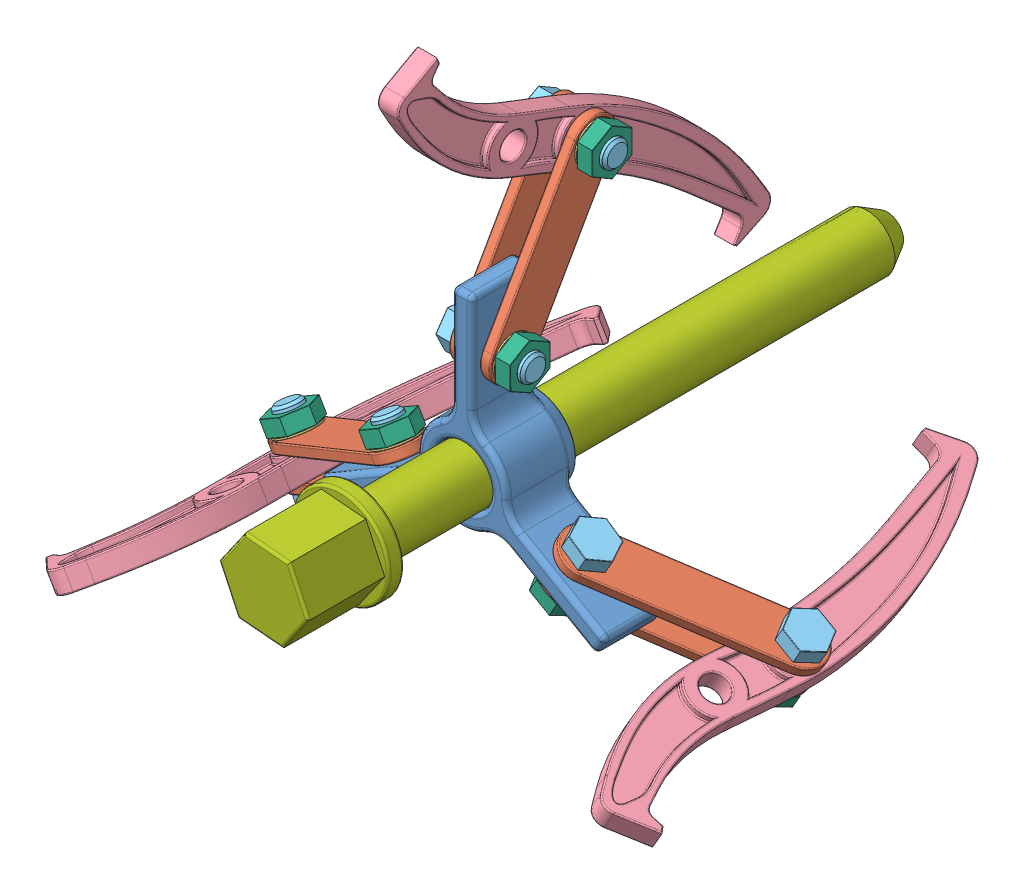
SolidWorks assembly Assem1, configuration Predeterminado. Lengths in mm.
Overall size (226.19 227.29 244).
29 component instances, 7 part files, 60 mates.
Components (placement in the parent):
- Part3-1: Part3 [Predeterminado] at (28.1141 -31.5333 0) size (110.79 96.48 29)
- Part1-1: Part1 [Predeterminado] at (2.5472 72.4071 -32.7339) x (0 0.869535 -0.493871) z (1 0 0) size (83 18 4)
- Part6-1: Part6 [Predeterminado] at (7.2972 39.1515 12) x (0 0 1) z (-1 0 0) size (16 16 0.75)
- Part1-4: Part1 [Predeterminado] at (-5.4528 40.2174 -14.451) x (0 -0.869535 0.493871) z (-1 0 0) size (83 18 4)
- Part2-3: Part2 [Predeterminado] at (2.5472 24.0134 4.9002) x (0 -0.857552 0.514397) z (-1 0 0) size (44.66 178.82 13.38)
- Part6-2: Part6 [Predeterminado] at (6.5472 95.6712 -20.1016) x (0 0 -1) z (1 0 0) size (16 16 0.75)
- Part1-5: Part1 [Predeterminado] at (-39.8155 -26.116 -13.2007) x (0.840042 0.484998 0.243119) z (0.5 -0.866025 0) size (83 18 4)
- Part1-6: Part1 [Predeterminado] at (-45.8155 -15.7237 -13.2007) x (0.840042 0.484998 0.243119) z (0.5 -0.866025 0) size (83 18 4)
- Part2-4: Part2 [Predeterminado] at (-25.6956 -8.7263 -5.8737) x (0.852447 0.492161 0.176386) z (0.5 -0.866025 0) size (44.66 178.82 13.38)
- Part6-3: Part6 [Predeterminado] at (-93.7725 -42.5457 -3.8027) x (0.75 0.433013 -0.5) z (0.5 -0.866025 0) size (16 16 0.75)
- Part6-4: Part6 [Predeterminado] at (-39.1698 -11.0208 12) x (0.422477 0.243917 -0.872936) z (0.5 -0.866025 0) size (16 16 0.75)
- Part1-7: Part1 [Predeterminado] at (60.7916 -26.0478 -35.7515) x (0.707952 -0.408736 -0.575968) z (-0.5 -0.866025 0) size (83 18 4)
- Part1-8: Part1 [Predeterminado] at (54.7916 -36.4401 -35.7515) x (0.707952 -0.408736 -0.575968) z (-0.5 -0.866025 0) size (83 18 4)
- Part2-6: Part2 [Predeterminado] at (10.4508 -10.8399 -32.3249) x (-0.86043 0.49677 0.113491) z (0.5 0.866025 0) size (44.66 178.82 13.38)
- Part6-5: Part6 [Predeterminado] at (73.531 -52.7441 -25.4379) x (0.75 -0.433013 -0.5) z (0.5 0.866025 0) size (16 16 0.75)
- Part6-6: Part6 [Predeterminado] at (27.8892 -25.5267 12) x (-0.760157 0.438877 -0.479113) z (-0.5 -0.866025 0) size (16 16 0.75)
- Part4B-1: Part4B [Predeterminado] at (85.031 -32.8255 -25.4379) x (0.75 -0.433013 0.5) z (-0.5 -0.866025 0) size (14 16.17 31)
- Part4B-2: Part4B [Predeterminado] at (39.0142 -6.2577 12) x (-0.721705 0.416676 -0.552741) z (-0.5 -0.866025 0) size (14 16.17 31)
- Part4B-3: Part4B [Predeterminado] at (-15.7028 95.6712 -20.1016) x (0 0 -1) z (1 0 0) size (14 16.17 31)
- Part4B-4: Part4B [Predeterminado] at (-15.7028 39.1515 12) x (0 0.43106 -0.902323) z (1 0 0) size (14 16.17 31)
- Part4B-5: Part4B [Predeterminado] at (-82.2725 -62.4643 -3.8027) x (0.75 0.433013 0.5) z (-0.5 0.866025 0) size (14 16.17 31)
- Part4B-6: Part4B [Predeterminado] at (-27.6698 -30.9394 12) x (0.75 0.433013 0.5) z (-0.5 0.866025 0) size (14 16.17 31)
- Part5B-1: Part5B [Predeterminado] at (-42.1698 -5.8247 12) x (0.75 0.433013 -0.5) z (0.5 -0.866025 0) size (15.59 18 6)
- Part5B-2: Part5B [Predeterminado] at (-96.7725 -37.3495 -3.8027) x (0.75 0.433013 -0.5) z (0.5 -0.866025 0) size (15.59 18 6)
- Part5B-3: Part5B [Predeterminado] at (24.5142 -31.3724 12) x (0.75 -0.433013 -0.5) z (0.5 0.866025 0) size (15.59 18 6)
- Part5B-4: Part5B [Predeterminado] at (70.531 -57.9402 -25.4379) x (0.75 -0.433013 -0.5) z (0.5 0.866025 0) size (15.59 18 6)
- Part5B-5: Part5B [Predeterminado] at (13.2972 39.1515 12) x (0 -0.017074 0.999854) z (-1 0 0) size (15.59 18 6)
- Part5B-6: Part5B [Predeterminado] at (13.2972 95.6712 -20.1016) x (0 0 1) z (-1 0 0) size (15.59 18 6)
- Part7B-1: Part7B [Predeterminado] at (-1.4528 0.6515 71.5964) x (-0.990638 -0.136515 0) z (0 0 -1) size (38 38 244)
Mates (geometry in assembly coordinates):
- Coincident5: coincident anti-aligned: plane of Part3-1 through (2.5472 24.3211 24) normal (1 0 0); plane of Part1-1 through (2.5472 39.1515 12) normal (-1 0 0)
- Concentric4: concentric aligned: cylinder of Part1-1; cylinder of Part6-1
- Concentric10: concentric anti-aligned: cylinder of Part3-1; cylinder of Part1-4
- Coincident12: coincident anti-aligned: plane of Part3-1 through (-5.4528 61.1515 24) normal (-1 0 0); plane of Part1-4 through (-5.4528 95.6712 -20.1016) normal (1 0 0)
- Concentric12: concentric anti-aligned: cylinder of Part1-4; cylinder of Part2-3
- Concentric13: concentric aligned: cylinder of Part1-1; cylinder of Part2-3
- Coincident16: coincident anti-aligned: plane of Part1-4 through (-5.4528 95.6712 -20.1016) normal (1 0 0); plane of Part2-3 through (-5.4528 141.5579 54.7254) normal (-1 0 0)
- Concentric14: concentric anti-aligned: cylinder of Part1-1; cylinder of Part6-2
- Coincident17: coincident anti-aligned: plane of Part1-1 through (6.5472 39.1515 12) normal (1 0 0); plane of Part6-2 through (6.5472 95.6712 -20.1016) normal (-1 0 0)
- Concentric16: concentric anti-aligned: cylinder of Part3-1; cylinder of Part1-6
- Coincident18: coincident anti-aligned: plane of Part3-1 through (-51.8473 -33.0626 24) normal (0.5 -0.866025 0); plane of Part1-5 through (-87.3975 -53.5875 -3.8027) normal (-0.5 0.866025 0)
- Coincident19: coincident anti-aligned: plane of Part3-1 through (-23.9513 -7.7192 24) normal (-0.5 0.866025 0); plane of Part1-6 through (-91.3975 -46.6593 -3.8027) normal (0.5 -0.866025 0)
- Concentric17: concentric anti-aligned: cylinder of Part1-5; cylinder of Part2-4
- Concentric18: concentric anti-aligned: cylinder of Part1-6; cylinder of Part2-4
- Coincident20: coincident anti-aligned: plane of Part1-6 through (-91.3975 -46.6593 -3.8027) normal (0.5 -0.866025 0); plane of Part2-4 through (-105.5377 -54.8232 82.4416) normal (-0.5 0.866025 0)
- Coincident21: coincident anti-aligned: plane of Part1-5 through (-87.3975 -53.5875 -3.8027) normal (-0.5 0.866025 0); plane of Part2-4 through (-101.5377 -61.7514 82.4416) normal (0.5 -0.866025 0)
- Concentric19: concentric anti-aligned: cylinder of Part1-6; cylinder of Part6-3
- Coincident22: coincident anti-aligned: plane of Part1-6 through (-93.3975 -43.1952 -3.8027) normal (-0.5 0.866025 0); plane of Part6-3 through (-93.3975 -43.1952 -3.8027) normal (0.5 -0.866025 0)
- Concentric20: concentric anti-aligned: cylinder of Part1-6; cylinder of Part6-4
- Coincident23: coincident anti-aligned: plane of Part1-6 through (-93.3975 -43.1952 -3.8027) normal (-0.5 0.866025 0); plane of Part6-4 through (-38.7948 -11.6703 12) normal (0.5 -0.866025 0)
- Concentric21: concentric anti-aligned: cylinder of Part3-1; cylinder of Part1-5
- Coincident24: coincident anti-aligned: plane of Part3-1 through (-51.8473 -33.0626 24) normal (0.5 -0.866025 0); plane of Part1-5 through (-87.3975 -53.5875 -3.8027) normal (-0.5 0.866025 0)
- Concentric23: concentric anti-aligned: cylinder of Part3-1; cylinder of Part1-7
- Coincident25: coincident anti-aligned: plane of Part3-1 through (52.9417 -26.1344 24) normal (0.5 0.866025 0); plane of Part1-7 through (33.8892 -15.1344 12) normal (-0.5 -0.866025 0)
- Concentric24: concentric anti-aligned: cylinder of Part3-1; cylinder of Part1-8
- Coincident26: coincident anti-aligned: plane of Part3-1 through (17.0457 -14.6474 24) normal (-0.5 -0.866025 0); plane of Part1-8 through (29.8892 -22.0626 12) normal (0.5 0.866025 0)
- Concentric29: concentric aligned: cylinder of Part1-7; cylinder of Part2-6
- Concentric30: concentric aligned: cylinder of Part1-8; cylinder of Part2-6
- Coincident32: coincident anti-aligned: plane of Part1-8 through (29.8892 -22.0626 12) normal (0.5 0.866025 0); plane of Part2-6 through (85.2722 -54.0381 61.6696) normal (-0.5 -0.866025 0)
- Coincident33: coincident anti-aligned: plane of Part1-7 through (33.8892 -15.1344 12) normal (-0.5 -0.866025 0); plane of Part2-6 through (89.2722 -47.1098 61.6696) normal (0.5 0.866025 0)
- Coincident34: coincident anti-aligned: plane of Part1-8 through (27.8892 -25.5267 12) normal (-0.5 -0.866025 0); plane of Part6-5 through (73.906 -52.0946 -25.4379) normal (0.5 0.866025 0)
- Concentric31: concentric aligned: cylinder of Part1-8; cylinder of Part6-5
- Concentric33: concentric anti-aligned: cylinder of Part1-8; cylinder of Part6-6
- Coincident36: coincident anti-aligned: plane of Part1-8 through (27.8892 -25.5267 12) normal (-0.5 -0.866025 0); plane of Part6-6 through (27.8892 -25.5267 12) normal (0.5 0.866025 0)
- Concentric34: concentric anti-aligned: cylinder of Part2-6; cylinder of Part4B-1
- Coincident37: coincident anti-aligned: plane of Part1-7 through (35.8892 -11.6703 12) normal (0.5 0.866025 0); plane of Part4B-1 through (81.906 -38.2382 -25.4379) normal (-0.5 -0.866025 0)
- Concentric36: concentric aligned: cylinder of Part3-1; cylinder of Part4B-2
- Coincident38: coincident anti-aligned: plane of Part1-7 through (35.8892 -11.6703 12) normal (0.5 0.866025 0); plane of Part4B-2 through (35.8892 -11.6703 12) normal (-0.5 -0.866025 0)
- Concentric37: concentric anti-aligned: cylinder of Part2-3; cylinder of Part4B-3
- Coincident39: coincident anti-aligned: plane of Part1-4 through (-9.4528 95.6712 -20.1016) normal (-1 0 0); plane of Part4B-3 through (-9.4528 95.6712 -20.1016) normal (1 0 0)
- Concentric39: concentric anti-aligned: cylinder of Part3-1; cylinder of Part4B-4
- Coincident41: coincident anti-aligned: plane of Part1-4 through (-9.4528 95.6712 -20.1016) normal (-1 0 0); plane of Part4B-4 through (-9.4528 39.1515 12) normal (1 0 0)
- Concentric40: concentric anti-aligned: cylinder of Part2-4; cylinder of Part4B-5
- Coincident42: coincident anti-aligned: plane of Part1-5 through (-85.3975 -57.0516 -3.8027) normal (0.5 -0.866025 0); plane of Part4B-5 through (-85.3975 -57.0516 -3.8027) normal (-0.5 0.866025 0)
- Concentric41: concentric anti-aligned: cylinder of Part3-1; cylinder of Part4B-6
- Coincident43: coincident anti-aligned: plane of Part1-5 through (-85.3975 -57.0516 -3.8027) normal (0.5 -0.866025 0); plane of Part4B-6 through (-30.7948 -25.5267 12) normal (-0.5 0.866025 0)
- Concentric42: concentric anti-aligned: cylinder of Part4B-6; cylinder of Part5B-1
- Coincident44: coincident anti-aligned: plane of Part6-4 through (-39.1698 -11.0208 12) normal (-0.5 0.866025 0); plane of Part5B-1 through (-46.964 -15.5208 12) normal (0.5 -0.866025 0)
- Concentric43: concentric anti-aligned: cylinder of Part4B-5; cylinder of Part5B-2
- Coincident45: coincident anti-aligned: plane of Part6-3 through (-93.7725 -42.5457 -3.8027) normal (-0.5 0.866025 0); plane of Part5B-2 through (-101.5667 -47.0457 -3.8027) normal (0.5 -0.866025 0)
- Concentric44: concentric anti-aligned: cylinder of Part4B-2; cylinder of Part5B-3
- Coincident46: coincident anti-aligned: plane of Part6-6 through (27.5142 -26.1763 12) normal (-0.5 -0.866025 0); plane of Part5B-3 through (23.6171 -23.9263 19.7942) normal (0.5 0.866025 0)
- Concentric45: concentric anti-aligned: cylinder of Part4B-1; cylinder of Part5B-4
- Coincident47: coincident anti-aligned: plane of Part6-5 through (73.531 -52.7441 -25.4379) normal (-0.5 -0.866025 0); plane of Part5B-4 through (69.6339 -50.4941 -17.6437) normal (0.5 0.866025 0)
- Concentric46: concentric anti-aligned: cylinder of Part4B-4; circle of Part5B-5
- Coincident49: coincident anti-aligned: plane of Part6-1 through (7.2972 39.1515 12) normal (1 0 0); plane of Part5B-5 through (7.2972 34.7852 4.1301) normal (-1 0 0)
- Coincident50: coincident anti-aligned: plane of Part1-1 through (6.5472 39.1515 12) normal (1 0 0); plane of Part6-1 through (6.5472 39.1515 12) normal (-1 0 0)
- Concentric47: concentric anti-aligned: cylinder of Part4B-3; cylinder of Part5B-6
- Coincident51: coincident anti-aligned: plane of Part6-2 through (7.2972 95.6712 -20.1016) normal (1 0 0); plane of Part5B-6 through (7.2972 91.1712 -27.8959) normal (-1 0 0)
- Concentric48: concentric anti-aligned: cylinder of Part3-1; cylinder of Part7B-1
